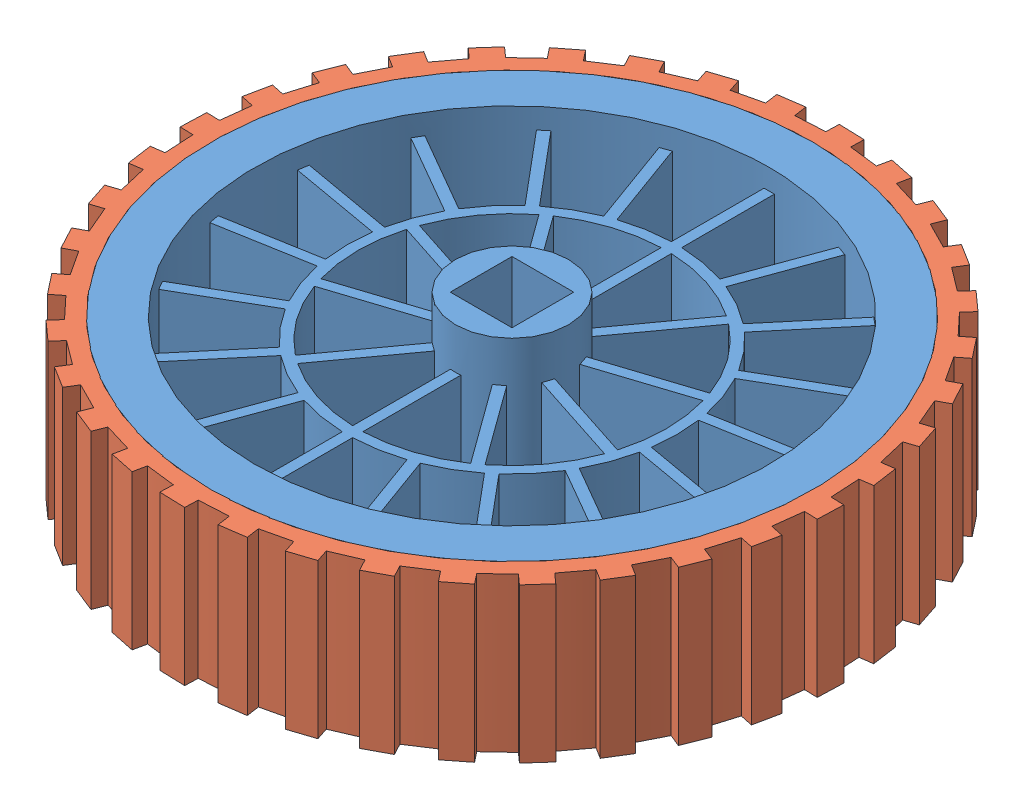
SolidWorks assembly Wheel Assembly, configuration Default. Lengths in mm.
Overall size (86.62 19 86.62).
2 component instances, 2 part files, 3 mates.
Components (placement in the parent):
- WheelRim.step-1: WheelRim.step [Default] at (-14.6667 -10.8085 9.9872) size (58.5 19 58.5)
- WheelTread.step-1: WheelTread.step [Default] at (-14.6667 -10.8085 9.9872) x (-0.881704 0 0.471803) z (-0.471803 0 -0.881704) size (64 15 64)
Mates (geometry in assembly coordinates):
- Concentric1: concentric: cylinder of WheelRim.step-1 through (-14.6667 -10.8085 9.9872) axis (0 -1 0) radius 27.25; cylinder of WheelTread.step-1 through (-14.6667 -10.8085 9.9872) axis (0 -1 0) radius 27.25
- Coincident1: coincident: plane of WheelRim.step-1 through (-14.6667 -8.8085 39.2372) normal (0 1 0); plane of WheelTread.step-1 through (-27.5233 -8.8085 -14.0393) normal (0 -1 0)
- Lock1: lock: unknown of WheelRim.step-1; unknown of WheelTread.step-1
